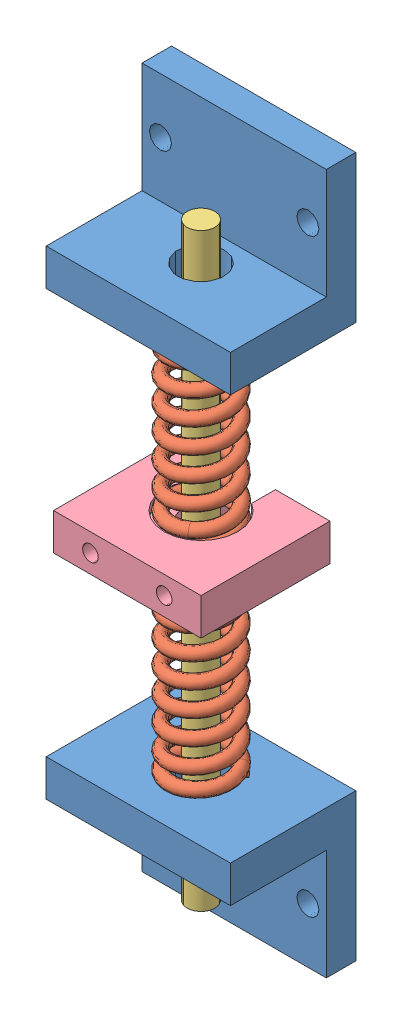
SolidWorks assembly spring-pack, configuration Default. Lengths in mm.
Overall size (31.75 120.65 23.5).
6 component instances, 4 part files, 10 mates.
Components (placement in the parent):
- y09-spring-holder-1: y09-spring-holder [Default] at origin size (31.75 25.4 21.59)
- Lee2E9-1: Lee2E9 [Default] at (0 46.1032 0) x (0.4998 0 0.866141) z (0 1 0) size (13.87 13.94 34.98)
- Lee2E9-2: Lee2E9 [Default] at (0 36.4468 0) x (0.987904 0 0.155065) z (0 -1 0) size (13.87 13.94 34.98)
- y09-spring-holder-2: y09-spring-holder [Default] at (0 82.55 0) x (-1 0 0) z (0 0 1) size (31.75 25.4 21.59)
- y16-center-spring-rod-1: y16-center-spring-rod [Default] at (0 89.0689 0) x (-0.828544 0 -0.559924) z (0 -1 0) size (4.76 4.76 101.6)
- y17-spring-center-1: y17-spring-center [Default] at (0 42.4549 0) x (1 0 0) z (0 -1 0) size (25.4 22.23 6.35)
Mates (geometry in assembly coordinates):
- Concentric1: concentric anti-aligned: cylinder of y09-spring-holder-1; line of Lee2E9-2
- Coincident2: coincident anti-aligned: line of Lee2E9-1; line of y09-spring-holder-2
- Coincident3: coincident aligned: plane of y09-spring-holder-1 through (-15.875 6.35 10.795) normal (0 0 1); plane of y09-spring-holder-2 through (15.875 76.2 10.795) normal (0 0 1)
- Distance1: distance = 69.85 mm anti-aligned: plane of y09-spring-holder-1 through (-15.875 6.35 10.795) normal (0 1 0); plane of y09-spring-holder-2 through (15.875 76.2 10.795) normal (0 -1 0)
- Coincident4: coincident anti-aligned: plane of Lee2E9-1; plane of y09-spring-holder-2 through (15.875 76.2 10.795) normal (0 -1 0)
- Coincident5: coincident anti-aligned: plane of y09-spring-holder-1 through (-15.875 6.35 10.795) normal (0 1 0); plane of Lee2E9-2
- Concentric2: concentric aligned: cylinder of y09-spring-holder-2; cylinder of y16-center-spring-rod-1
- Concentric3: concentric aligned: cylinder of y16-center-spring-rod-1; cylinder of y17-spring-center-1
- Parallel1: parallel aligned: plane of y09-spring-holder-2 through (-15.875 76.2 -10.795) normal (-1 0 0); plane of y17-spring-center-1 through (-12.7 39.2799 -9.525) normal (-1 0 0)
- Concentric4: concentric anti-aligned: cylinder of y09-spring-holder-1; cylinder of y16-center-spring-rod-1
